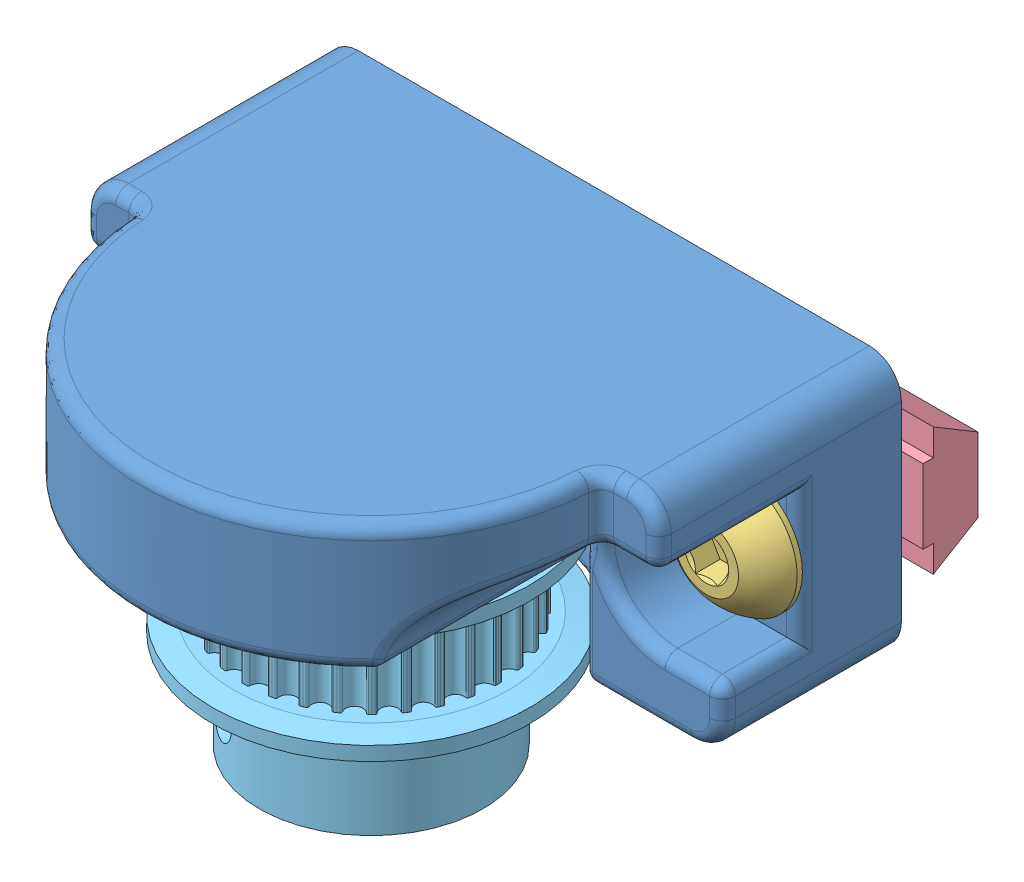
SolidWorks assembly 10mm_Rod_End_Bearing_Assembly, configuration Default. Lengths in mm.
Overall size (48.98 27.53 42.5).
8 component instances, 6 part files, 19 mates.
Components (placement in the parent):
- Bearing_Holder-1: Bearing_Holder [Default] at origin size (45 20.07 37)
- 6900ZZ_10x22x6-1: 6900ZZ_10x22x6 [5972K164] at (0 3 19) x (1 0 0) z (0 1 0) size (22 22 6)
- 5mmX12mm_Buttonhead(McMaster_92095A210)-3: 5mmX12mm_Buttonhead(McMaster_92095A210) [92095A210] at (18 0 10.75) x (-0.866025 -0.5 0) z (0 0 1) size (9.5 9.5 15.22)
- 5mmX12mm_Buttonhead(McMaster_92095A210)-2: 5mmX12mm_Buttonhead(McMaster_92095A210) [92095A210] at (-18 0 10.75) x (0.866025 0.5 0) z (0 0 1) size (9.5 9.5 15.22)
- HNTTSN5-5-1: HNTTSN5-5 [Default] at (-18 0 -1.2) x (0 0 1) z (-1 0 0) size (4.3 10 10)
- HNTTSN5-5-2: HNTTSN5-5 [Default] at (18 0 -1.2) x (0 0 1) z (-1 0 0) size (4.3 10 10)
- GT2_Aluminum_Timing_Pulley_32_Tooth-1: GT2_Aluminum_Timing_Pulley_32_Tooth [Default] at (0 -0.5 19) x (0 -1 0) z (0.46829 0 -0.883575) size (17.03 24.87 24.87)
- 10mmx16mmx0.5mm_SHim(McMaster_90214A422)-1: 10mmx16mmx0.5mm_SHim(McMaster_90214A422) [Default] at (0 -0.5 19) x (1 0 0) z (0 1 0) size (16 16 0.5)
Mates (geometry in assembly coordinates):
- Concentric1: concentric anti-aligned: cylinder of Bearing_Holder-1 through (0 6 19) axis (0 -1 0) radius 11.1; cylinder of 6900ZZ_10x22x6-1 through (0 6 19) axis (0 1 0) radius 11
- Coincident1: coincident anti-aligned: plane of Bearing_Holder-1 through (0 6 19) normal (0 -1 0); plane of 6900ZZ_10x22x6-1 through (0 6 8.3) normal (0 1 0)
- Parallel1: parallel anti-aligned: plane of 6900ZZ_10x22x6-1 through (0 3 19) normal (0 0 -1); plane of assembly through (0 0 0) normal (0 0 1)
- Concentric51: concentric anti-aligned: cylinder of Bearing_Holder-1 through (18 0 37) axis (0 0 -1) radius 2.6; cylinder of 5mmX12mm_Buttonhead(McMaster_92095A210)-3 through (18 0 10.75) axis (0 0 1) radius 4.75
- Coincident61: coincident anti-aligned: plane of Bearing_Holder-1 through (18 0 8) normal (0 0 1); plane of 5mmX12mm_Buttonhead(McMaster_92095A210)-3 through (15.625 4.1136 8) normal (0 0 -1)
- Concentric61: concentric anti-aligned: cylinder of Bearing_Holder-1 through (-18 0 37) axis (0 0 -1) radius 2.6; cylinder of 5mmX12mm_Buttonhead(McMaster_92095A210)-2 through (-18 0 10.75) axis (0 0 1) radius 4.75
- Coincident71: coincident anti-aligned: plane of Bearing_Holder-1 through (-18 0 8) normal (0 0 1); plane of 5mmX12mm_Buttonhead(McMaster_92095A210)-2 through (-15.625 -4.1136 8) normal (0 0 -1)
- Concentric7: concentric anti-aligned: cylinder of 5mmX12mm_Buttonhead(McMaster_92095A210)-2 through (-18 0 10.75) axis (0 0 1) radius 4.75; cylinder of HNTTSN5-5-1 through (-18 0 -1.2) axis (0 0 -1) radius 2.067
- Distance1: distance = 2 mm anti-aligned: plane of HNTTSN5-5-1 through (-23 -5 -2) normal (0 0 1); plane of Bearing_Holder-1 through (20 7.5 0) normal (0 0 -1)
- Parallel2: parallel anti-aligned: plane of Bearing_Holder-1 through (-22.5 -7.5 37) normal (-1 0 0); plane of HNTTSN5-5-1 through (-13 0 -1.2) normal (1 0 0)
- Concentric8: concentric anti-aligned: cylinder of 5mmX12mm_Buttonhead(McMaster_92095A210)-3 through (18 0 10.75) axis (0 0 1) radius 4.75; cylinder of HNTTSN5-5-2 through (18 0 -1.2) axis (0 0 -1) radius 2.067
- Distance2: distance = 2 mm anti-aligned: plane of Bearing_Holder-1 through (20 7.5 0) normal (0 0 -1); plane of HNTTSN5-5-2 through (13 -5 -2) normal (0 0 1)
- Parallel3: parallel aligned: plane of Bearing_Holder-1 through (22.5 -7.5 37) normal (1 0 0); plane of HNTTSN5-5-2 through (23 0 -1.2) normal (1 0 0)
- Parallel4: parallel aligned: plane of Bearing_Holder-1 through (-20 -10 37) normal (0 -1 0); plane of 5mmX12mm_Buttonhead(McMaster_92095A210)-3 through (18.866 1.5 8.825) normal (0 -1 0)
- Parallel5: parallel aligned: plane of Bearing_Holder-1 through (-20 -10 37) normal (0 -1 0); plane of 5mmX12mm_Buttonhead(McMaster_92095A210)-2 through (-17.134 1.5 8.825) normal (0 -1 0)
- Concentric62: concentric aligned: cylinder of 6900ZZ_10x22x6-1 through (0 6 19) axis (0 1 0) radius 5; cylinder of GT2_Aluminum_Timing_Pulley_32_Tooth-1 through (0 -31.7004 19) axis (0 1 0) radius 5.01
- Concentric63: concentric anti-aligned: cylinder of 6900ZZ_10x22x6-1 through (0 6 19) axis (0 1 0) radius 5; cylinder of 10mmx16mmx0.5mm_SHim(McMaster_90214A422)-1 through (0 0 19) axis (0 -1 0) radius 5
- Coincident72: coincident anti-aligned: plane of 6900ZZ_10x22x6-1 through (0 0 13.7) normal (0 -1 0); plane of 10mmx16mmx0.5mm_SHim(McMaster_90214A422)-1 through (0 0 19) normal (0 1 0)
- Coincident73: coincident anti-aligned: plane of GT2_Aluminum_Timing_Pulley_32_Tooth-1 through (0 -0.5 19) normal (0 1 0); plane of 10mmx16mmx0.5mm_SHim(McMaster_90214A422)-1 through (0 -0.5 19) normal (0 -1 0)
